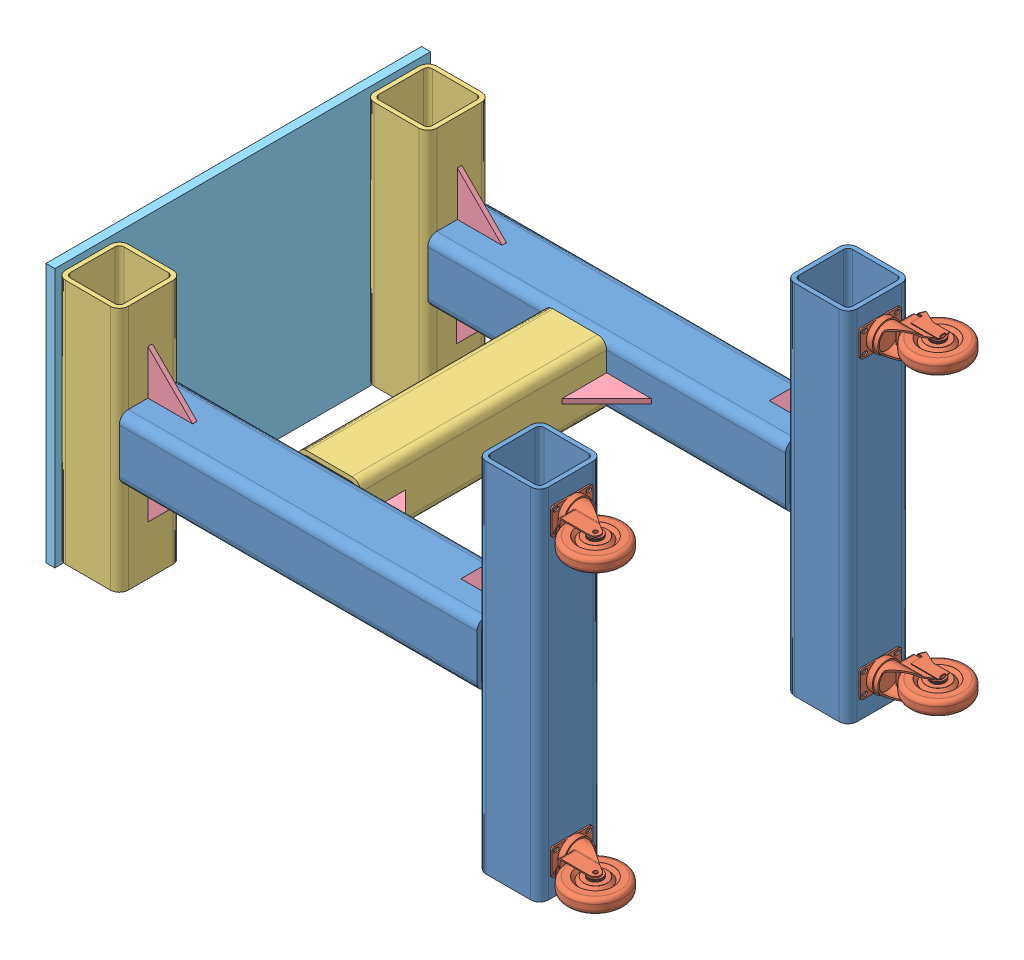
SolidWorks assembly Mobilno_Postolje, configuration Default. Lengths in mm.
Overall size (628.11 400 446.56).
26 component instances, 6 part files, 88 mates.
Components (placement in the parent):
- Postolje-1: Postolje [Default] at origin size (400 70 70)
- Postolje-3: Postolje [Default] at (435 195 0) x (0 -1 0) z (0 0 1) size (400 70 70)
- Postolje-5: Postolje [Default] at (400 0 345) x (-1 0 0) z (0 0 -1) size (400 70 70)
- Kotac-1: Kotac [Default] at (434.5085 -140.1857 -30.0028) x (-1 0 0) z (0 1 0) size (78.11 73.82 32.58)
- Postolje_2-1: Postolje_2 [Default] at (165 0 -90) x (0 0 1) z (-1 0 0) size (275 70 70)
- Postolje-7: Postolje [Default] at (435 195 345) x (0 -1 0) z (-1 0 0) size (400 70 70)
- Postolje_2-2: Postolje_2 [Default] at (-35 260 345) x (0 -1 0) z (0 0 1) size (275 70 70)
- Postolje_2-3: Postolje_2 [Default] at (-35 260 0) x (0 -1 0) z (0 0 1) size (275 70 70)
- Kotac-2: Kotac [Default] at (434.5085 189.6518 -30.0028) x (-1 0 0) z (0 1 0) size (78.11 73.82 32.58)
- Kotac-3: Kotac [Default] at (434.5085 130.1857 375.0028) x (-1 0 0) z (0 -1 0) size (78.11 73.82 32.58)
- Kotac-4: Kotac [Default] at (434.5085 -199.6518 375.0028) x (-1 0 0) z (0 -1 0) size (78.11 73.82 32.58)
- Part-1: Part [Default] at (400 35 3) x (0 0 -1) z (1 0 0) size (5 50 50)
- Part-2: Part [Default] at (400 -35 343) x (0 0 1) z (1 0 0) size (5 50 50)
- Part-3: Part [Default] at (400 -35 -2) x (0 0 1) z (1 0 0) size (5 50 50)
- Part-4: Part [Default] at (400 35 348) x (0 0 -1) z (1 0 0) size (5 50 50)
- Part-5: Part [Default] at (200 3 35) x (0 -1 0) z (-1 0 0) size (5 50 50)
- Part-6: Part [Default] at (0 35 343) x (0 0 1) z (-1 0 0) size (5 50 50)
- Part-7: Part [Default] at (200 -3 310) x (0 1 0) z (-1 0 0) size (5 50 50)
- Part-8: Part [Default] at (0 35 2) x (0 0 -1) z (0 -1 0) size (5 50 50)
- Part-9: Part [Default] at (0 -35 -2) x (0 0 1) z (0 1 0) size (5 50 50)
- Part-10: Part [Default] at (0 -35 343) x (0 0 1) z (0 1 0) size (5 50 50)
- Ploca-1: Ploca [Default] at (-110 -2.5 172) x (0 0 -1) z (0 -1 0) size (420 10 290)
- countersunk flat head cross recess screw_iso-8: countersunk flat head cross recess screw_iso [ISO 7046-1 - M6 x 20 - Z - 20N] at (-80 92.5 -3) size (20 11.3 11.3)
- countersunk flat head cross recess screw_iso-9: countersunk flat head cross recess screw_iso [ISO 7046-1 - M6 x 20 - Z - 20N] at (-80 92.5 347) size (20 11.3 11.3)
- countersunk flat head cross recess screw_iso-10: countersunk flat head cross recess screw_iso [ISO 7046-1 - M6 x 20 - Z - 20N] at (-80 -97.5 347) size (20 11.3 11.3)
- countersunk flat head cross recess screw_iso-11: countersunk flat head cross recess screw_iso [ISO 7046-1 - M6 x 20 - Z - 20N] at (-80 -97.5 -3) size (20 11.3 11.3)
Mates (geometry in assembly coordinates):
- Coincident2: coincident anti-aligned: plane of Postolje-1 through (0 25 -25) normal (-1 0 0); plane of extender_scaled-2 through (0 -205 25) normal (1 0 0)
- Coincident3: coincident aligned: plane of Postolje-1 through (400 -25 35) normal (0 0 1); plane of extender_scaled-2 through (-10 -205 35) normal (0 0 1)
- Coincident4: coincident aligned: plane of Postolje-1 through (400 -25 35) normal (0 0 1); plane of Postolje-3 through (410 -205 35) normal (0 0 1)
- Coincident5: coincident anti-aligned: plane of Postolje-1 through (400 25 -25) normal (1 0 0); plane of Postolje-3 through (400 -205 25) normal (-1 0 0)
- Coincident6: coincident aligned: plane of extender_scaled-2 through (-10 195 25) normal (0 1 0); plane of Postolje-3 through (460 195 -25) normal (0 1 0)
- Coincident8: coincident anti-aligned: plane of Postolje-1 through (400 -25 35) normal (0 0 1); plane of extender_scaled-4 through (220.8025 25 35) normal (0 0 -1)
- Coincident9: coincident aligned: plane of Postolje-1 through (400 35 -25) normal (0 1 0); plane of extender_scaled-4 through (220.8025 35 435) normal (0 1 0)
- Coincident10: coincident anti-aligned: plane of extender_scaled-4 through (220.8025 25 435) normal (0 0 1); plane of Postolje-5 through (0 -25 310) normal (0 0 -1)
- Coincident11: coincident aligned: plane of extender_scaled-4 through (220.8025 35 435) normal (0 1 0); plane of Postolje-5 through (0 35 370) normal (0 1 0)
- Coincident12: coincident anti-aligned: plane of Postolje-3 through (470 -205 -25) normal (1 0 0); plane of Kotac-1 through (470 -158.0125 19.8625) normal (-1 0 0)
- Coincident13: coincident anti-aligned: plane of Postolje-1 through (400 -25 35) normal (0 0 1); plane of Postolje_2-1 through (165 0 35) normal (0 0 -1)
- Coincident14: coincident aligned: plane of Postolje-1 through (400 -35 25) normal (0 -1 0); plane of Postolje_2-1 through (140 -35 310) normal (0 -1 0)
- Coincident15: coincident anti-aligned: plane of Postolje-5 through (0 -25 310) normal (0 0 -1); plane of Postolje_2-1 through (190 25 310) normal (0 0 1)
- Coincident16: coincident aligned: plane of Postolje-5 through (0 -35 320) normal (0 -1 0); plane of Postolje_2-1 through (140 -35 310) normal (0 -1 0)
- Coincident17: coincident: line of Postolje-1 through (400 35 -25) axis (0 0 1); plane of Postolje-5 through (400 25 370) normal (1 0 0)
- Distance3: distance = 200 mm aligned: plane of Postolje-5 through (400 25 370) normal (1 0 0); plane of Postolje_2-1 through (200 25 310) normal (1 0 0)
- Distance4: distance = 160 mm aligned: plane of Postolje-1 through (400 35 -25) normal (0 1 0); plane of Postolje-3 through (460 195 -25) normal (0 1 0)
- Coincident18: coincident anti-aligned: plane of Postolje-5 through (0 25 370) normal (-1 0 0); plane of Postolje-6 through (0 -205 320) normal (1 0 0)
- Coincident19: coincident aligned: plane of Postolje-5 through (0 25 380) normal (0 0 1); plane of Postolje-6 through (-60 -205 380) normal (0 0 1)
- Coincident20: coincident aligned: plane of Postolje-2 through (-10 195 25) normal (0 1 0); plane of Postolje-6 through (-10 195 320) normal (0 1 0)
- Coincident21: coincident anti-aligned: plane of Postolje-5 through (400 25 370) normal (1 0 0); plane of Postolje-7 through (400 -205 320) normal (-1 0 0)
- Coincident23: coincident aligned: plane of Postolje-5 through (0 25 380) normal (0 0 1); plane of Postolje-7 through (460 -205 380) normal (0 0 1)
- Coincident24: coincident aligned: plane of Postolje-3 through (460 195 -25) normal (0 1 0); plane of Postolje-7 through (460 195 370) normal (0 1 0)
- Coincident25: coincident anti-aligned: plane of Postolje-5 through (0 25 370) normal (-1 0 0); plane of Postolje_2-2 through (0 -140 320) normal (1 0 0)
- Coincident26: coincident aligned: plane of Postolje-5 through (0 25 380) normal (0 0 1); plane of Postolje_2-2 through (-60 -140 380) normal (0 0 1)
- Distance5: distance = 100 mm aligned: plane of Postolje-5 through (0 35 370) normal (0 1 0); plane of Postolje_2-2 through (-35 135 345) normal (0 1 0)
- Coincident29: coincident anti-aligned: plane of Postolje-1 through (0 25 -25) normal (-1 0 0); plane of Postolje_2-3 through (0 -140 -25) normal (1 0 0)
- Coincident30: coincident aligned: plane of Postolje-1 through (400 -25 35) normal (0 0 1); plane of Postolje_2-3 through (-60 -140 35) normal (0 0 1)
- Coincident31: coincident aligned: plane of Postolje_2-2 through (-35 135 345) normal (0 1 0); plane of Postolje_2-3 through (-35 135 0) normal (0 1 0)
- Coincident32: coincident anti-aligned: plane of Postolje-7 through (470 -205 370) normal (1 0 0); plane of Kotac-4 through (470 -181.825 325.1375) normal (-1 0 0)
- Coincident33: coincident anti-aligned: plane of Postolje-7 through (470 -205 370) normal (1 0 0); plane of Kotac-3 through (470 148.0125 325.1375) normal (-1 0 0)
- Coincident34: coincident anti-aligned: plane of Postolje-3 through (470 -205 -25) normal (1 0 0); plane of Kotac-2 through (470 171.825 19.8625) normal (-1 0 0)
- Distance6: distance = 20 mm aligned: plane of Kotac-3 through (470 175 364.825) normal (0 1 0); plane of Postolje-7 through (460 195 370) normal (0 1 0)
- Distance8: distance = 20 mm: line of Kotac-4 through (470 -185 325.1375) axis (0 0 1); plane of Postolje-7 through (460 -205 370) normal (0 -1 0)
- Distance9: distance = 12 mm aligned: plane of Kotac-4 through (470 -181.825 368) normal (0 0 1); plane of Postolje-7 through (460 -205 380) normal (0 0 1)
- Distance10: distance = 12 mm aligned: plane of Kotac-3 through (470 148.0125 368) normal (0 0 1); plane of Postolje-7 through (460 -205 380) normal (0 0 1)
- Distance14: distance = 12 mm: plane of Postolje-3 through (460 -205 -35) normal (0 0 -1); line of Kotac-2 through (470 171.825 -23) axis (0 -1 0)
- Distance12: distance = 20 mm: line of Kotac-2 through (470 175 19.8625) axis (0 0 -1); plane of Postolje-3 through (460 195 -25) normal (0 1 0)
- Distance15: distance = 12 mm: point of Kotac-1; plane of Postolje-3 through (460 -205 -35) normal (0 0 -1)
- Distance16: distance = 20 mm aligned: plane of Kotac-1 through (470 -185 -19.825) normal (0 -1 0); plane of Postolje-3 through (460 -205 -25) normal (0 -1 0)
- Coincident45: coincident anti-aligned: plane of Postolje-1 through (400 35 -25) normal (0 1 0); plane of Part-1 through (400 35 -2) normal (0 -1 0)
- Coincident46: coincident anti-aligned: plane of Postolje-3 through (400 -205 25) normal (-1 0 0); plane of Part-1 through (400 85 -2) normal (1 0 0)
- Distance17: distance = 32 mm: plane of Part-1 through (400 35 3) normal (0 0 1); line of Postolje-1 through (400 25 35) axis (-1 0 0)
- Coincident48: coincident anti-aligned: plane of Postolje-3 through (400 -205 25) normal (-1 0 0); plane of Part-3 through (400 -85 3) normal (1 0 0)
- Coincident49: coincident anti-aligned: plane of Postolje-1 through (400 -35 25) normal (0 -1 0); plane of Part-3 through (400 -35 3) normal (0 1 0)
- Distance18: distance = 32 mm aligned: plane of Part-3 through (400 -35 3) normal (0 0 1); plane of Postolje-3 through (410 -205 35) normal (0 0 1)
- Coincident51: coincident anti-aligned: plane of Postolje-7 through (400 -205 320) normal (-1 0 0); plane of Part-4 through (400 85 343) normal (1 0 0)
- Coincident52: coincident anti-aligned: plane of Postolje-5 through (0 35 370) normal (0 1 0); plane of Part-4 through (400 35 343) normal (0 -1 0)
- Distance19: distance = 32 mm aligned: plane of Part-4 through (400 35 348) normal (0 0 1); plane of Postolje-5 through (0 25 380) normal (0 0 1)
- Coincident54: coincident anti-aligned: plane of Postolje-7 through (400 -205 320) normal (-1 0 0); plane of Part-2 through (400 -85 348) normal (1 0 0)
- Coincident55: coincident anti-aligned: plane of Postolje-5 through (0 -35 320) normal (0 -1 0); plane of Part-2 through (400 -35 348) normal (0 1 0)
- Distance20: distance = 32 mm aligned: plane of Part-2 through (400 -35 348) normal (0 0 1); plane of Postolje-5 through (0 25 380) normal (0 0 1)
- Coincident57: coincident anti-aligned: plane of Postolje_2-1 through (200 25 310) normal (1 0 0); plane of Part-5 through (200 -2 85) normal (-1 0 0)
- Coincident58: coincident anti-aligned: plane of Postolje-1 through (400 -25 35) normal (0 0 1); plane of Part-5 through (200 -2 35) normal (0 0 -1)
- Distance21: distance = 32 mm aligned: plane of Part-5 through (200 3 35) normal (0 1 0); plane of Postolje-1 through (400 35 -25) normal (0 1 0)
- Coincident68: coincident anti-aligned: plane of Postolje_2-1 through (200 25 310) normal (1 0 0); plane of Part-7 through (200 2 260) normal (-1 0 0)
- Coincident69: coincident anti-aligned: plane of Postolje-5 through (0 -25 310) normal (0 0 -1); plane of Part-7 through (200 2 310) normal (0 0 1)
- Distance24: distance = 32 mm aligned: plane of Part-7 through (200 -3 310) normal (0 -1 0); plane of Postolje-5 through (0 -35 320) normal (0 -1 0)
- Coincident71: coincident anti-aligned: plane of Postolje-5 through (0 35 370) normal (0 1 0); plane of Part-6 through (0 35 348) normal (0 -1 0)
- Coincident72: coincident anti-aligned: plane of Postolje_2-2 through (0 -140 320) normal (1 0 0); plane of Part-6 through (0 85 348) normal (-1 0 0)
- Distance25: distance = 32 mm aligned: plane of Part-6 through (0 35 348) normal (0 0 1); plane of Postolje-5 through (0 25 380) normal (0 0 1)
- Coincident74: coincident anti-aligned: plane of Postolje_2-3 through (0 -140 -25) normal (1 0 0); plane of Part-8 through (0 35 -3) normal (-1 0 0)
- Coincident75: coincident anti-aligned: plane of Postolje-1 through (400 35 -25) normal (0 1 0); plane of Part-8 through (50 35 -3) normal (0 -1 0)
- Distance26: distance = 32 mm aligned: plane of Part-8 through (0 35 -3) normal (0 0 -1); plane of Postolje-1 through (400 25 -35) normal (0 0 -1)
- Coincident77: coincident anti-aligned: plane of Postolje_2-3 through (0 -140 -25) normal (1 0 0); plane of Part-9 through (0 -35 3) normal (-1 0 0)
- Coincident78: coincident anti-aligned: plane of Postolje-1 through (400 -35 25) normal (0 -1 0); plane of Part-9 through (50 -35 3) normal (0 1 0)
- Distance27: distance = 32 mm aligned: plane of Part-9 through (0 -35 3) normal (0 0 1); plane of Postolje-1 through (400 -25 35) normal (0 0 1)
- Coincident80: coincident anti-aligned: plane of Postolje-5 through (0 -35 320) normal (0 -1 0); plane of Part-10 through (50 -35 348) normal (0 1 0)
- Coincident81: coincident anti-aligned: plane of Postolje_2-2 through (0 -140 320) normal (1 0 0); plane of Part-10 through (0 -35 348) normal (-1 0 0)
- Distance28: distance = 32 mm aligned: plane of Part-10 through (0 -35 348) normal (0 0 1); plane of Postolje-5 through (0 25 380) normal (0 0 1)
- Coincident83: coincident anti-aligned: plane of Postolje_2-2 through (-70 -140 370) normal (-1 0 0); plane of Ploca-1 through (-70 -2.5 172) normal (1 0 0)
- Distance30: distance = 2 mm aligned: plane of Postolje_2-2 through (-60 -140 380) normal (0 0 1); plane of Ploca-1 through (-70 -147.5 382) normal (0 0 1)
- Distance29: distance = 7.5 mm aligned: plane of Ploca-1 through (-70 142.5 382) normal (0 1 0); plane of Postolje_2-2 through (-35 135 345) normal (0 1 0)
- Concentric1: concentric anti-aligned: cylinder of Ploca-1 through (-80 92.5 347) axis (1 0 0) radius 5.65; cylinder of countersunk flat head cross recess screw_iso-2 through (-86.35 92.5 347) axis (-1 0 0) radius 3
- Coincident85: coincident aligned: plane of Ploca-1 through (-80 -2.5 172) normal (-1 0 0); plane of countersunk flat head cross recess screw_iso-2 through (-80 92.5 347) normal (-1 0 0)
- Concentric2: concentric anti-aligned: cylinder of Ploca-1 through (-80 -97.5 347) axis (1 0 0) radius 5.65; cylinder of countersunk flat head cross recess screw_iso-1 through (-86.35 -97.5 347) axis (-1 0 0) radius 3
- Coincident87: coincident aligned: plane of Ploca-1 through (-80 -2.5 172) normal (-1 0 0); plane of countersunk flat head cross recess screw_iso-1 through (-80 -97.5 347) normal (-1 0 0)
- Concentric3: concentric anti-aligned: cylinder of Ploca-1 through (-80 92.5 -3) axis (1 0 0) radius 5.65; cylinder of countersunk flat head cross recess screw_iso-3 through (-86.35 92.5 -3) axis (-1 0 0) radius 3
- Coincident88: coincident aligned: plane of Ploca-1 through (-80 -2.5 172) normal (-1 0 0); plane of countersunk flat head cross recess screw_iso-3 through (-80 92.5 -3) normal (-1 0 0)
- Concentric4: concentric anti-aligned: cylinder of Ploca-1 through (-80 -97.5 -3) axis (1 0 0) radius 5.65; cylinder of countersunk flat head cross recess screw_iso-4 through (-140.4774 -97.5 -3) axis (-1 0 0) radius 3
- Concentric5: concentric: cylinder of Ploca-1 through (-80 92.5 347) axis (1 0 0) radius 5.65; cylinder of countersunk flat head cross recess screw_iso-9 through (-86.35 92.5 347) axis (-1 0 0) radius 3
- Coincident89: coincident aligned: plane of Ploca-1 through (-80 -2.5 172) normal (-1 0 0); plane of countersunk flat head cross recess screw_iso-9 through (-80 92.5 347) normal (-1 0 0)
- Concentric6: concentric: cylinder of Ploca-1 through (-80 -97.5 347) axis (1 0 0) radius 5.65; cylinder of countersunk flat head cross recess screw_iso-10 through (-86.35 -97.5 347) axis (-1 0 0) radius 3
- Coincident90: coincident aligned: plane of Ploca-1 through (-80 -2.5 172) normal (-1 0 0); plane of countersunk flat head cross recess screw_iso-10 through (-80 -97.5 347) normal (-1 0 0)
- Concentric7: concentric: cylinder of Ploca-1 through (-80 92.5 -3) axis (1 0 0) radius 5.65; cylinder of countersunk flat head cross recess screw_iso-8 through (-86.35 92.5 -3) axis (-1 0 0) radius 3
- Coincident91: coincident aligned: plane of Ploca-1 through (-80 -2.5 172) normal (-1 0 0); plane of countersunk flat head cross recess screw_iso-8 through (-80 92.5 -3) normal (-1 0 0)
- Concentric8: concentric: cylinder of Ploca-1 through (-80 -97.5 -3) axis (1 0 0) radius 5.65; cylinder of countersunk flat head cross recess screw_iso-11 through (-86.35 -97.5 -3) axis (-1 0 0) radius 3
- Coincident92: coincident aligned: plane of Ploca-1 through (-80 -2.5 172) normal (-1 0 0); plane of countersunk flat head cross recess screw_iso-11 through (-80 -97.5 -3) normal (-1 0 0)
